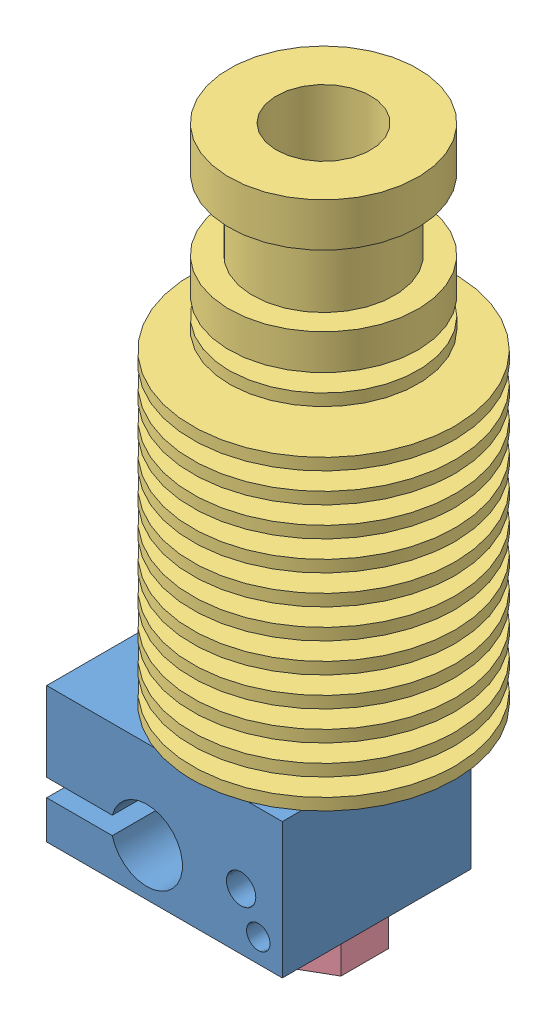
SolidWorks assembly E3D V6 1.75 Uni model, configuration Default. Lengths in mm.
Overall size (26.95 61.85 22.9).
4 component instances, 4 part files, 6 mates.
Components (placement in the parent):
- block^E3D V6 1.75 Uni model-1: block^E3D V6 1.75 Uni model [Default] at (3.1723 13.0752 15.8249) size (20 12.14 16) (virtual)
- break^E3D V6 1.75 Uni model-1: break^E3D V6 1.75 Uni model [Default] at (8.6723 14.5752 15.8249) size (7.18 22.4 6.95) (virtual)
- sink^E3D V6 1.75 Uni model-1: sink^E3D V6 1.75 Uni model [Default] at (8.6723 42.5778 15.8249) x (0.999633 0 0.027082) z (-0.027082 0 0.999633) size (22.3 42.99 22.3) (virtual)
- nozzle^E3D V6 1.75 Uni model-1: nozzle^E3D V6 1.75 Uni model [Default] at (8.6723 2.0752 15.8249) size (7 12.82 8.08) (virtual)
Mates (geometry in assembly coordinates):
- Concentric1: concentric anti-aligned: cylinder of break^E3D V6 1.75 Uni model-1 through (8.6723 8.3085 15.8249) axis (0 -1 0) radius 2.825; cylinder of sink^E3D V6 1.75 Uni model-1 through (8.6723 57.9278 15.8249) axis (0 1 0) radius 4
- Coincident1: coincident: circle of break^E3D V6 1.75 Uni model-1; cone of sink^E3D V6 1.75 Uni model-1 through (8.6723 36.6051 15.8249) axis (0 1 0)
- Concentric4: concentric anti-aligned: cylinder of block^E3D V6 1.75 Uni model-1 through (8.6723 7.3242 15.8249) axis (0 1 0) radius 2.5; cylinder of break^E3D V6 1.75 Uni model-1 through (8.6723 8.3085 15.8249) axis (0 -1 0) radius 1.4
- Coincident6: coincident anti-aligned: plane of break^E3D V6 1.75 Uni model-1 through (8.6723 14.5752 15.8249) normal (0 -1 0); plane of nozzle^E3D V6 1.75 Uni model-1 through (8.6723 14.5752 15.8249) normal (0 1 0)
- Concentric5: concentric anti-aligned: cylinder of block^E3D V6 1.75 Uni model-1 through (8.6723 7.3242 15.8249) axis (0 1 0) radius 2.5; cone of nozzle^E3D V6 1.75 Uni model-1 through (8.6723 14.887 15.8249) axis (0 -1 0)
- Distance1: distance = 0.25 mm anti-aligned: plane of nozzle^E3D V6 1.75 Uni model-1 through (6.1723 7.0752 15.8249) normal (0 1 0); plane of block^E3D V6 1.75 Uni model-1 through (3.1723 7.3252 15.8249) normal (0 -1 0)
